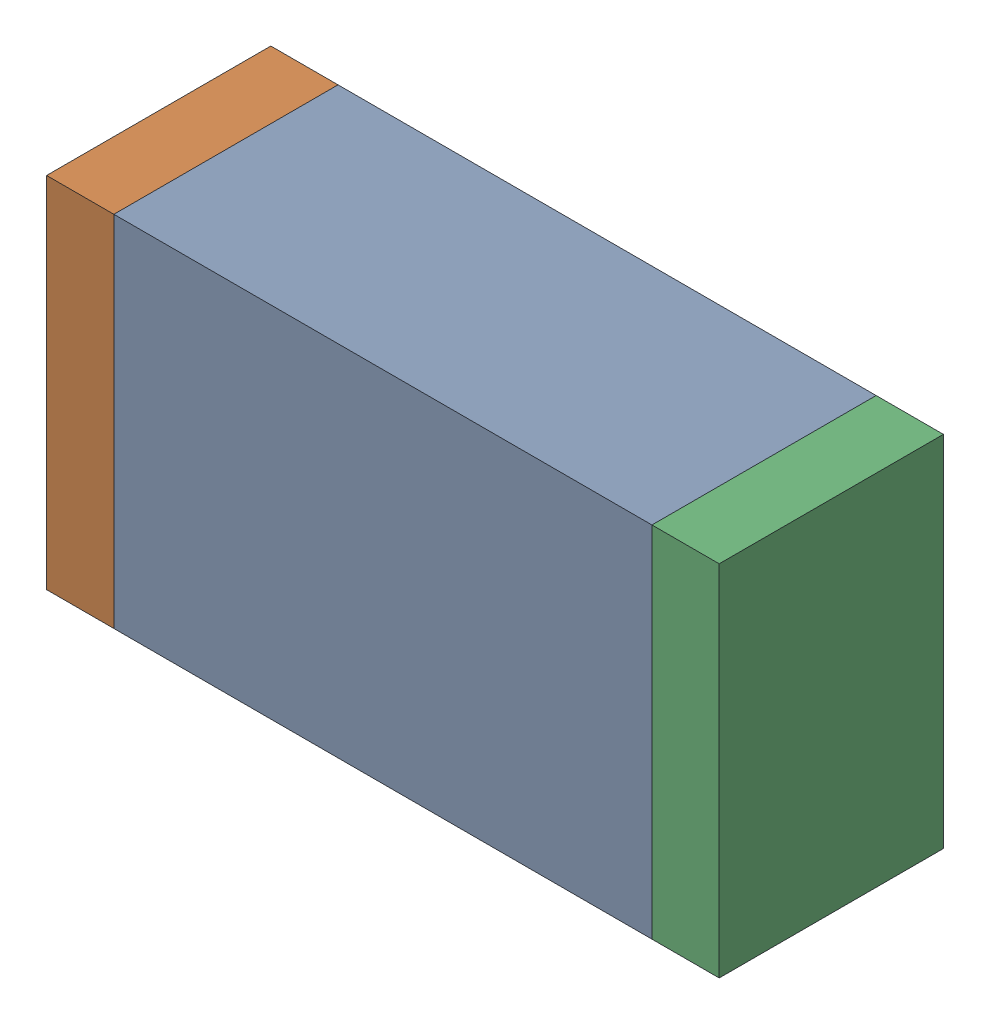
SolidWorks assembly R19, configuration Default. Lengths in mm.
Overall size (1.5 0.8 0.5).
6 component instances, 2 part files, 0 mates.
Components (placement in the parent):
- 836752368-1: 836752368 [Default] at (118.55 40.75 0) size (1.2 0.8 0.5)
  - Extruded-1: Extruded [Default] at origin size (1.2 0.8 0.5)
- 836752496-1: 836752496 [Default] at (117.875 40.75 0) size (0.15 0.8 0.5)
  - Extruded_2-1: Extruded_2 [Default] at origin size (0.15 0.8 0.5)
- 836752496-2: 836752496 [Default] at (119.225 40.75 0) size (0.15 0.8 0.5)
  - Extruded_2-1: Extruded_2 [Default] at origin size (0.15 0.8 0.5)
